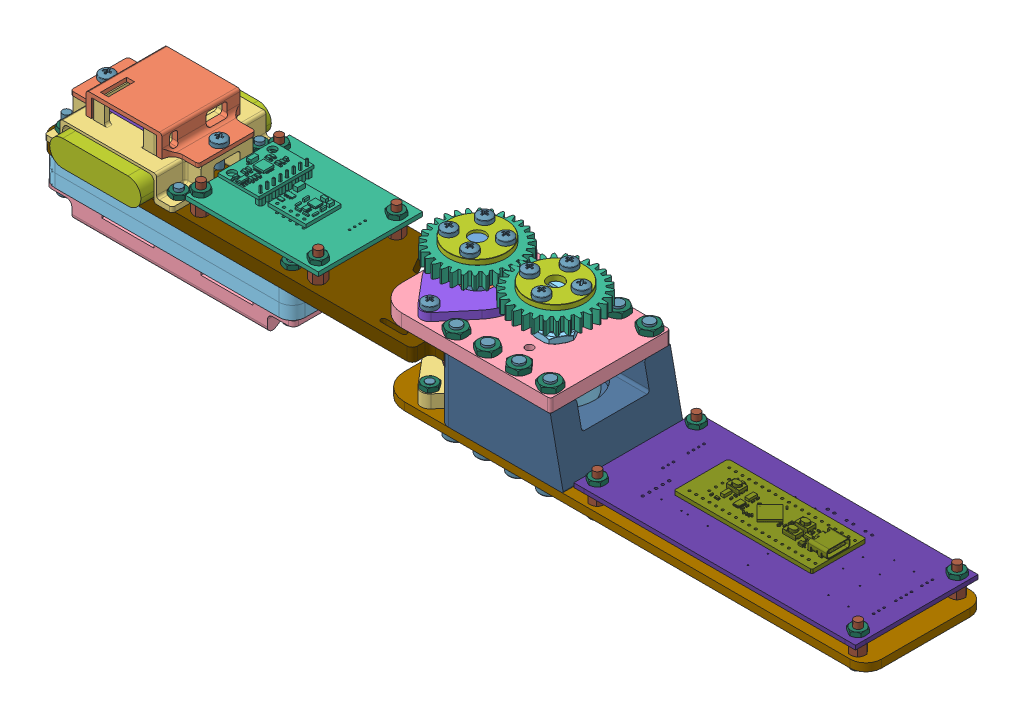
SolidWorks assembly canh_tay_cang_tay_asm, configuration Default. Lengths in mm.
Overall size (320 57.82 50).
135 component instances, 26 part files, 3 mates.
Components (placement in the parent):
- phan_cang_tay_asm-1: phan_cang_tay_asm [Default] at (73.3024 69.8746 76.7713) size (193.86 57.82 47.69)
  - truc_khuy_tay_6mm-1: truc_khuy_tay_6mm [Default] at (-13.0536 7.0359 41.2843) size (6 45 6)
  - instrument ball bearing_68_am-1: instrument ball bearing_68_am [AFBMA 12.1.4.1 - 0060-19 - 8,DE,NC,8_68] at (-13.0536 10.0359 41.2843) x (0 -1 0) z (0.814441 0 0.580247) size (6 19 19)
  - instrument ball bearing_68_am-2: instrument ball bearing_68_am [AFBMA 12.1.4.1 - 0060-19 - 8,DE,NC,8_68] at (-13.0536 33.0359 41.2843) x (0 -1 0) z (0.463151 0 0.88628) size (6 19 19)
  - thanh_noi_cang_tay_1-1: thanh_noi_cang_tay_1 [Default] at (-13.0536 7.0359 41.2843) x (-1 0 0) z (0 0 -1) size (30 5 43)
  - khuy_tay-1: khuy_tay [Default] at (16.9464 36.0359 41.2843) x (-1 0 0) z (0 -1 0) size (67 46 5)
  - RV24 v6.step-1: RV24 v6.step [Default] at (16.9464 24.0359 41.2843) x (0 1 0) z (0 0 -1) size (34 30.6 24.6)
  - banh_rang-1: banh_rang [Default] at (-13.8942 39.1454 73.2027) x (0 1 0) z (-0.508693 0 -0.860948) size (12 31.88 32)
    - spur gear_iso_m3-1: spur gear_iso_m3 [ISO - Spur gear 1M 30T 20PA 10FW ---S30B25H18L6.0N] at (1.8905 16.9604 27.0525) size (5 31.88 32)
    - mat_bich_6mm-1: mat_bich_6mm [Default] at (13.8905 16.9604 27.0525) x (0 0 1) z (0 -1 0) size (22 12 22)
  - mieng_che_o_lan-1: mieng_che_o_lan [Default] at (-13.0536 36.0359 41.2843) x (-1 0 0) z (0 0 -1) size (30 3 43)
  - thanh_cang_tay-1: thanh_cang_tay [Default] at (102.9464 4.0359 41.2843) x (-1 0 0) z (0 1 0) size (187 46 3)
  - noi_cang_tay-1: noi_cang_tay [Default] at (21.9464 7.0359 41.2843) x (-1 0 0) z (0 0 -1) size (47.89 24 46)
  - hexagonal_spacer_MF_M3_H05_HEX5_FTD3_MTL8.step-2: hexagonal_spacer_MF_M3_H05_HEX5_FTD3_MTL8.step [Default] at (151.9464 12.0359 60.2843) x (-0.310043 0 0.950723) z (0 -1 0) size (5.78 5.01 10.97)
  - mieng_dem_cang_tay-1: mieng_dem_cang_tay [Default] at (117.9464 4.0359 41.2843) x (-1 0 0) z (0 0 -1) size (70 6.47 35)
  - mieng_dem_cang_tay_2-1: mieng_dem_cang_tay_2 [Default] at (30.9464 4.0359 41.2843) x (-1 0 0) z (0 0 -1) size (68 6.47 30)
  - pan head cross recess screw_iso-1: pan head cross recess screw_iso [ISO 7045 - M3 x 8 - Z - 8N] at (147.9464 -0.3641 27.2843) x (0 1 0) z (0 0 1) size (10.35 5.6 5.6)
  - pan head cross recess screw_iso-2: pan head cross recess screw_iso [ISO 7045 - M3 x 8 - Z - 8N] at (147.9464 -0.3641 55.2843) x (0 1 0) z (0 0 1) size (10.35 5.6 5.6)
  - pan head cross recess screw_iso-3: pan head cross recess screw_iso [ISO 7045 - M3 x 8 - Z - 8N] at (87.9464 -0.3641 55.2843) x (0 1 0) z (0 0 1) size (10.35 5.6 5.6)
  - pan head cross recess screw_iso-4: pan head cross recess screw_iso [ISO 7045 - M3 x 8 - Z - 8N] at (87.9464 -0.3641 27.2843) x (0 1 0) z (0 0 1) size (10.35 5.6 5.6)
  - pan head cross recess screw_iso-5: pan head cross recess screw_iso [ISO 7045 - M3 x 8 - Z - 8N] at (60.9464 -0.3641 52.2843) x (0 1 0) z (0 0 1) size (10.35 5.6 5.6)
  - pan head cross recess screw_iso-6: pan head cross recess screw_iso [ISO 7045 - M3 x 8 - Z - 8N] at (60.9464 -0.3641 30.2843) x (0 1 0) z (0 0 1) size (10.35 5.6 5.6)
  - pan head cross recess screw_iso-9: pan head cross recess screw_iso [ISO 7045 - M3 x 6 - Z - 6N] at (0.9464 9.4359 30.2843) x (0 -1 0) z (0 0 1) size (8.35 5.6 5.6)
  - pan head cross recess screw_iso-10: pan head cross recess screw_iso [ISO 7045 - M3 x 6 - Z - 6N] at (0.9464 9.4359 52.2843) x (0 -1 0) z (0 0 1) size (8.35 5.6 5.6)
  - hex thin nut chamfered gradeab_iso-3: hex thin nut chamfered gradeab_iso [ISO - 4035 - M3 - N] at (0.9464 0.2359 30.2843) x (1 0 0) z (0 -1 0) size (5.5 6.35 1.8)
  - hex thin nut chamfered gradeab_iso-4: hex thin nut chamfered gradeab_iso [ISO - 4035 - M3 - N] at (0.9464 0.2359 52.2843) x (1 0 0) z (0 -1 0) size (5.5 6.35 1.8)
  - hex thin nut chamfered gradeab_iso-5: hex thin nut chamfered gradeab_iso [ISO - 4035 - M3 - N] at (60.9464 8.8359 30.2843) x (1 0 0) z (0 1 0) size (5.5 6.35 1.8)
  - hex thin nut chamfered gradeab_iso-6: hex thin nut chamfered gradeab_iso [ISO - 4035 - M3 - N] at (60.9464 8.8359 52.2843) x (1 0 0) z (0 1 0) size (5.5 6.35 1.8)
  - hex thin nut chamfered gradeab_iso-7: hex thin nut chamfered gradeab_iso [ISO - 4035 - M3 - N] at (87.9464 8.8359 55.2843) x (1 0 0) z (0 1 0) size (5.5 6.35 1.8)
  - hex thin nut chamfered gradeab_iso-8: hex thin nut chamfered gradeab_iso [ISO - 4035 - M3 - N] at (87.9464 8.8359 27.2843) x (1 0 0) z (0 1 0) size (5.5 6.35 1.8)
  - hex thin nut chamfered gradeab_iso-9: hex thin nut chamfered gradeab_iso [ISO - 4035 - M3 - N] at (147.9464 8.8359 27.2843) x (1 0 0) z (0 1 0) size (5.5 6.35 1.8)
  - hex thin nut chamfered gradeab_iso-10: hex thin nut chamfered gradeab_iso [ISO - 4035 - M3 - N] at (147.9464 8.8359 55.2843) x (1 0 0) z (0 1 0) size (5.5 6.35 1.8)
  - pan head cross recess screw_iso-18: pan head cross recess screw_iso [ISO 7045 - M4 x 35 - Z - 35N] at (33.9464 0.9359 22.2843) x (0 1 0) z (0 0 1) size (38.02 8 8)
  - pan head cross recess screw_iso-19: pan head cross recess screw_iso [ISO 7045 - M4 x 35 - Z - 35N] at (21.9464 0.9359 22.2843) x (0 1 0) z (0 0 1) size (38.02 8 8)
  - pan head cross recess screw_iso-20: pan head cross recess screw_iso [ISO 7045 - M4 x 35 - Z - 35N] at (9.9464 0.9359 22.2843) x (0 1 0) z (0 0 1) size (38.02 8 8)
  - pan head cross recess screw_iso-21: pan head cross recess screw_iso [ISO 7045 - M4 x 35 - Z - 35N] at (33.9464 0.9359 60.2843) x (0 1 0) z (0 0 1) size (38.02 8 8)
  - pan head cross recess screw_iso-22: pan head cross recess screw_iso [ISO 7045 - M4 x 35 - Z - 35N] at (21.9464 0.9359 60.2843) x (0 1 0) z (0 0 1) size (38.02 8 8)
  - pan head cross recess screw_iso-23: pan head cross recess screw_iso [ISO 7045 - M4 x 35 - Z - 35N] at (9.9464 0.9359 60.2843) x (0 1 0) z (0.916024 0 0.401125) size (38.02 8 8)
  - hex thin nut chamfered gradeab_iso-11: hex thin nut chamfered gradeab_iso [ISO - 4035 - M4 - N] at (33.9464 38.2359 22.2843) x (1 0 0) z (0 1 0) size (7 8.08 2.2)
  - hex thin nut chamfered gradeab_iso-12: hex thin nut chamfered gradeab_iso [ISO - 4035 - M4 - N] at (21.9464 38.2359 22.2843) x (1 0 0) z (0 1 0) size (7 8.08 2.2)
  - hex thin nut chamfered gradeab_iso-13: hex thin nut chamfered gradeab_iso [ISO - 4035 - M4 - N] at (9.9464 38.2359 22.2843) x (1 0 0) z (0 1 0) size (7 8.08 2.2)
  - hex thin nut chamfered gradeab_iso-14: hex thin nut chamfered gradeab_iso [ISO - 4035 - M4 - N] at (33.9464 36.0359 60.2843) x (0.993976 0 -0.109599) z (0 -1 0) size (7 8.08 2.2)
  - hex thin nut chamfered gradeab_iso-15: hex thin nut chamfered gradeab_iso [ISO - 4035 - M4 - N] at (21.9464 38.2359 60.2843) x (-0.185733 0 -0.9826) z (0 1 0) size (7 8.08 2.2)
  - hex thin nut chamfered gradeab_iso-16: hex thin nut chamfered gradeab_iso [ISO - 4035 - M4 - N] at (9.9464 38.2359 60.2843) x (1 0 0) z (0 1 0) size (7 8.08 2.2)
  - pan head cross recess screw_iso-25: pan head cross recess screw_iso [ISO 7045 - M3 x 10 - Z - 10N] at (-6.166 55.4359 37.2148) x (0 -1 0) z (0 0 1) size (12.35 5.6 5.6)
  - pan head cross recess screw_iso-26: pan head cross recess screw_iso [ISO 7045 - M3 x 10 - Z - 10N] at (-8.9841 55.4359 48.1719) x (0 -1 0) z (0 0 1) size (12.35 5.6 5.6)
  - pan head cross recess screw_iso-27: pan head cross recess screw_iso [ISO 7045 - M3 x 10 - Z - 10N] at (-19.9412 55.4359 45.3539) x (0 -1 0) z (-0.140483 0 -0.990083) size (12.35 5.6 5.6)
  - pan head cross recess screw_iso-28: pan head cross recess screw_iso [ISO 7045 - M3 x 10 - Z - 10N] at (-17.1232 55.4359 34.3967) x (0 -1 0) z (0 0 1) size (12.35 5.6 5.6)
  - pan head cross recess screw_iso-29: pan head cross recess screw_iso [ISO 7045 - M3 x 10 - Z - 10N] at (24.6096 55.4359 38.9877) x (0 -1 0) z (-0.805474 0 0.592631) size (12.35 5.6 5.6)
  - pan head cross recess screw_iso-30: pan head cross recess screw_iso [ISO 7045 - M3 x 10 - Z - 10N] at (14.6497 55.4359 33.6211) x (0 -1 0) z (0 0 1) size (12.35 5.6 5.6)
  - pan head cross recess screw_iso-31: pan head cross recess screw_iso [ISO 7045 - M3 x 10 - Z - 10N] at (9.2831 55.4359 43.581) x (0 -1 0) z (0 0 1) size (12.35 5.6 5.6)
  - pan head cross recess screw_iso-32: pan head cross recess screw_iso [ISO 7045 - M3 x 10 - Z - 10N] at (19.243 55.4359 48.9476) x (0 -1 0) z (0 0 1) size (12.35 5.6 5.6)
  - banh_rang-3: banh_rang [Default] at (47.7291 39.1454 49.7644) x (0 1 0) z (-0.957906 0 0.287083) size (12 31.88 32)
    - spur gear_iso_m3-1: spur gear_iso_m3 [ISO - Spur gear 1M 30T 20PA 10FW ---S30B25H18L6.0N] at (1.8905 16.9604 27.0525) size (5 31.88 32)
    - mat_bich_6mm-1: mat_bich_6mm [Default] at (13.8905 16.9604 27.0525) x (0 0 1) z (0 -1 0) size (22 12 22)
  - hex thin nut chamfered gradeab_iso-18: hex thin nut chamfered gradeab_iso [ISO - 4035 - M3 - N] at (19.243 44.2359 48.9476) x (1 0 0) z (0 -1 0) size (5.5 6.35 1.8)
  - hex thin nut chamfered gradeab_iso-19: hex thin nut chamfered gradeab_iso [ISO - 4035 - M3 - N] at (9.2831 44.2359 43.581) x (1 0 0) z (0 -1 0) size (5.5 6.35 1.8)
  - hex thin nut chamfered gradeab_iso-20: hex thin nut chamfered gradeab_iso [ISO - 4035 - M3 - N] at (14.6497 44.2359 33.6211) x (1 0 0) z (0 -1 0) size (5.5 6.35 1.8)
  - hex thin nut chamfered gradeab_iso-21: hex thin nut chamfered gradeab_iso [ISO - 4035 - M3 - N] at (24.6096 44.2359 38.9877) x (1 0 0) z (0 -1 0) size (5.5 6.35 1.8)
  - hex thin nut chamfered gradeab_iso-22: hex thin nut chamfered gradeab_iso [ISO - 4035 - M3 - N] at (-6.166 44.2359 37.2148) x (1 0 0) z (0 -1 0) size (5.5 6.35 1.8)
  - hex thin nut chamfered gradeab_iso-23: hex thin nut chamfered gradeab_iso [ISO - 4035 - M3 - N] at (-8.9841 44.2359 48.1719) x (1 0 0) z (0 -1 0) size (5.5 6.35 1.8)
  - hex thin nut chamfered gradeab_iso-24: hex thin nut chamfered gradeab_iso [ISO - 4035 - M3 - N] at (-17.1232 44.2359 34.3967) x (1 0 0) z (0 -1 0) size (5.5 6.35 1.8)
  - hex thin nut chamfered gradeab_iso-25: hex thin nut chamfered gradeab_iso [ISO - 4035 - M3 - N] at (-19.9412 44.2359 45.3539) x (1 0 0) z (0 -1 0) size (5.5 6.35 1.8)
  - pan head cross recess screw_iso-37: pan head cross recess screw_iso [ISO 7045 - M3 x 10 - Z - 10N] at (-13.0536 41.4359 59.5343) x (0 -1 0) z (0 0 1) size (12.35 5.6 5.6)
  - pan head cross recess screw_iso-38: pan head cross recess screw_iso [ISO 7045 - M3 x 10 - Z - 10N] at (-13.0536 41.4359 23.0343) x (0 -1 0) z (0 0 1) size (12.35 5.6 5.6)
  - pan head cross recess screw_iso-39: pan head cross recess screw_iso [ISO 7045 - M3 x 10 - Z - 10N] at (-13.0536 1.6359 59.5343) x (0 1 0) z (0 0 1) size (12.35 5.6 5.6)
  - pan head cross recess screw_iso-40: pan head cross recess screw_iso [ISO 7045 - M3 x 10 - Z - 10N] at (-13.0536 1.6359 23.0343) x (0 1 0) z (0 0 1) size (12.35 5.6 5.6)
  - hex thin nut chamfered gradeab_iso-30: hex thin nut chamfered gradeab_iso [ISO - 4035 - M3 - N] at (-13.0536 29.2359 23.0343) x (1 0 0) z (0 -1 0) size (5.5 6.35 1.8)
  - hex thin nut chamfered gradeab_iso-31: hex thin nut chamfered gradeab_iso [ISO - 4035 - M3 - N] at (-13.0536 13.8359 23.0343) x (1 0 0) z (0 1 0) size (5.5 6.35 1.8)
  - hex thin nut chamfered gradeab_iso-33: hex thin nut chamfered gradeab_iso [ISO - 4035 - M3 - N] at (-13.0536 12.0359 59.5343) x (0.832178 0 -0.554509) z (0 -1 0) size (5.5 6.35 1.8)
  - hex thin nut chamfered gradeab_iso-34: hex thin nut chamfered gradeab_iso [ISO - 4035 - M3 - N] at (-13.0536 29.2359 59.5343) x (1 0 0) z (0 -1 0) size (5.5 6.35 1.8)
  - pan head cross recess screw_iso-59: pan head cross recess screw_iso [ISO 7045 - M4 x 35 - Z - 35N] at (-2.0536 0.9359 60.2843) x (0 1 0) z (-0.660079 0 0.751196) size (38.02 8 8)
  - hex thin nut chamfered gradeab_iso-45: hex thin nut chamfered gradeab_iso [ISO - 4035 - M4 - N] at (-2.0536 38.2359 60.2843) x (1 0 0) z (0 1 0) size (7 8.08 2.2)
  - hexagonal_spacer_MF_M3_H05_HEX5_FTD3_MTL8.step-3: hexagonal_spacer_MF_M3_H05_HEX5_FTD3_MTL8.step [Default] at (151.9464 12.0359 22.2843) x (-0.310043 0 0.950723) z (0 -1 0) size (5.78 5.01 10.97)
  - hexagonal_spacer_MF_M3_H05_HEX5_FTD3_MTL8.step-4: hexagonal_spacer_MF_M3_H05_HEX5_FTD3_MTL8.step [Default] at (51.9464 12.0359 60.2843) x (-0.310043 0 0.950723) z (0 -1 0) size (5.78 5.01 10.97)
  - hexagonal_spacer_MF_M3_H05_HEX5_FTD3_MTL8.step-5: hexagonal_spacer_MF_M3_H05_HEX5_FTD3_MTL8.step [Default] at (51.9464 12.0359 22.2843) x (-0.310043 0 0.950723) z (0 -1 0) size (5.78 5.01 10.97)
  - pan head cross recess screw_iso-60: pan head cross recess screw_iso [ISO 7045 - M3 x 8 - Z - 8N] at (151.9464 1.6359 22.2843) x (0 1 0) z (0 0 1) size (10.35 5.6 5.6)
  - pan head cross recess screw_iso-61: pan head cross recess screw_iso [ISO 7045 - M3 x 8 - Z - 8N] at (151.9464 1.6359 60.2843) x (0 1 0) z (0 0 1) size (10.35 5.6 5.6)
  - pan head cross recess screw_iso-62: pan head cross recess screw_iso [ISO 7045 - M3 x 8 - Z - 8N] at (51.9464 1.6359 60.2843) x (0 1 0) z (0 0 1) size (10.35 5.6 5.6)
  - pan head cross recess screw_iso-63: pan head cross recess screw_iso [ISO 7045 - M3 x 8 - Z - 8N] at (51.9464 1.6359 22.2843) x (0 1 0) z (0 0 1) size (10.35 5.6 5.6)
  - control_glove_v0.1.step-1: control_glove_v0.1.step [Default] at (56.9464 12.0359 56.2843) x (1 0 0) z (0 1 0) size (108 47 7.4)
    - MiniF4x1Cx_V31_3D.step-1: MiniF4x1Cx_V31_3D.step [Default] at (68.0647 25.992 4.15) x (-1 0 0) z (0 0 1) size (52.81 20.78 5.3)
      - COMPOUND.step-1: COMPOUND.step [Default] at origin size (52.81 20.78 5.3)
    - _autosave-control_glove_v0.1 PCB.step-1: _autosave-control_glove_v0.1 PCB.step [Default] at origin size (108 47 1.6)
  - hex thin nut chamfered gradeab_iso-46: hex thin nut chamfered gradeab_iso [ISO - 4035 - M3 - N] at (51.9464 15.4359 22.2843) x (1 0 0) z (0 1 0) size (5.5 6.35 1.8)
  - hex thin nut chamfered gradeab_iso-47: hex thin nut chamfered gradeab_iso [ISO - 4035 - M3 - N] at (51.9464 15.4359 60.2843) x (1 0 0) z (0 1 0) size (5.5 6.35 1.8)
  - hex thin nut chamfered gradeab_iso-48: hex thin nut chamfered gradeab_iso [ISO - 4035 - M3 - N] at (151.9464 15.4359 22.2843) x (1 0 0) z (0 1 0) size (5.5 6.35 1.8)
  - hex thin nut chamfered gradeab_iso-49: hex thin nut chamfered gradeab_iso [ISO - 4035 - M3 - N] at (151.9464 15.4359 60.2843) x (1 0 0) z (0 1 0) size (5.5 6.35 1.8)
- phan_canh_tay_asm-1: phan_canh_tay_asm [Default] at (-0.0131 19.8199 138.0557) size (161 41.97 50)
  - thanh_khuy_tay-1: thanh_khuy_tay [Default] at (60.2619 70.5906 -20) x (-1 0 0) z (0 1 0) size (161 40 5)
  - mat_bich_6mm-1: mat_bich_6mm [Default] at (60.2619 75.0906 -20) x (-1 0 0) z (0 0 1) size (22 12 22)
  - dem_mat_bich-2: dem_mat_bich [Default] at (60.2619 75.0906 -20) x (0 0 1) z (-1 0 0) size (22 5 22)
  - hexagonal_spacer_MF_M3_H05_HEX5_FTD3_MTL8.step-1: hexagonal_spacer_MF_M3_H05_HEX5_FTD3_MTL8.step [Default] at (14.2619 78.0906 -35) x (-0.957206 0 -0.289407) z (0 -1 0) size (5.78 5.01 10.97)
  - nap_mach_sac-1: nap_mach_sac [Default] at (-60.2381 83.0906 -20) x (-1 0 0) z (0 0 -1) size (49 8.5 30)
  - vo_pin-1: vo_pin [Default] at (-60.2381 83.0906 -20) x (-1 0 0) z (0 0 -1) size (49 17 42)
  - mieng_dem_canh_tay - 2-1: mieng_dem_canh_tay - 2 [Default] at (-30.7381 58.0906 -20) x (-1 0 0) z (0 0 -1) size (95 8.47 38)
  - mieng_lot_dem_canh_tay_1-3: mieng_lot_dem_canh_tay_1 [Default] at (-30.7381 63.0906 -20) x (-1 0 0) z (0 0 -1) size (96 5 40)
  - mieng_lot_dem_canh_tay_1-4: mieng_lot_dem_canh_tay_1 [Default] at (-30.7381 58.0906 -20) x (-1 0 0) z (0 0 -1) size (96 5 40)
  - pan head cross recess screw_iso-33: pan head cross recess screw_iso [ISO 7045 - M3 x 10 - Z - 10N] at (68.2619 78.4906 -20) x (0 -1 0) z (0.29969 0 0.954037) size (12.35 5.6 5.6)
  - pan head cross recess screw_iso-34: pan head cross recess screw_iso [ISO 7045 - M3 x 10 - Z - 10N] at (60.2619 78.4906 -12) x (0 -1 0) z (0.29969 0 0.954037) size (12.35 5.6 5.6)
  - pan head cross recess screw_iso-35: pan head cross recess screw_iso [ISO 7045 - M3 x 10 - Z - 10N] at (52.2619 78.4906 -20) x (0 -1 0) z (0.29969 0 0.954037) size (12.35 5.6 5.6)
  - pan head cross recess screw_iso-36: pan head cross recess screw_iso [ISO 7045 - M3 x 10 - Z - 10N] at (60.2619 78.4906 -28) x (0 -1 0) z (0.29969 0 0.954037) size (12.35 5.6 5.6)
  - hex thin nut chamfered gradeab_iso-26: hex thin nut chamfered gradeab_iso [ISO - 4035 - M3 - N] at (52.2619 66.2906 -20) x (0.954037 0 -0.29969) z (0 -1 0) size (5.5 6.35 1.8)
  - hex thin nut chamfered gradeab_iso-27: hex thin nut chamfered gradeab_iso [ISO - 4035 - M3 - N] at (60.2619 66.2906 -28) x (0.954037 0 -0.29969) z (0 -1 0) size (5.5 6.35 1.8)
  - hex thin nut chamfered gradeab_iso-28: hex thin nut chamfered gradeab_iso [ISO - 4035 - M3 - N] at (60.2619 66.2906 -12) x (0.954037 0 -0.29969) z (0 -1 0) size (5.5 6.35 1.8)
  - hex thin nut chamfered gradeab_iso-29: hex thin nut chamfered gradeab_iso [ISO - 4035 - M3 - N] at (68.2619 66.2906 -20) x (0.954037 0 -0.29969) z (0 -1 0) size (5.5 6.35 1.8)
  - pan head cross recess screw_iso-41: pan head cross recess screw_iso [ISO 7045 - M3 x 20 - Z - 20N] at (4.2619 53.6906 -35) x (0 1 0) z (0.29969 0 0.954037) size (22.35 5.6 5.6)
  - pan head cross recess screw_iso-42: pan head cross recess screw_iso [ISO 7045 - M3 x 20 - Z - 20N] at (4.2619 53.6906 -5) x (0 1 0) z (0.29969 0 0.954037) size (22.35 5.6 5.6)
  - pan head cross recess screw_iso-43: pan head cross recess screw_iso [ISO 7045 - M3 x 20 - Z - 20N] at (-30.7381 53.6906 -5) x (0 1 0) z (0.29969 0 0.954037) size (22.35 5.6 5.6)
  - pan head cross recess screw_iso-44: pan head cross recess screw_iso [ISO 7045 - M3 x 20 - Z - 20N] at (-30.7381 53.6906 -35) x (0 1 0) z (0.29969 0 0.954037) size (22.35 5.6 5.6)
  - pan head cross recess screw_iso-47: pan head cross recess screw_iso [ISO 7045 - M3 x 8 - Z - 8N] at (14.2619 65.6906 -5) x (0 1 0) z (0.29969 0 0.954037) size (10.35 5.6 5.6)
  - pan head cross recess screw_iso-48: pan head cross recess screw_iso [ISO 7045 - M3 x 8 - Z - 8N] at (14.2619 65.6906 -35) x (0 1 0) z (0.29969 0 0.954037) size (10.35 5.6 5.6)
  - pan head cross recess screw_iso-51: pan head cross recess screw_iso [ISO 7045 - M3 x 8 - Z - 8N] at (-38.7381 67.6906 -4.5) x (0 1 0) z (0.29969 0 0.954037) size (10.35 5.6 5.6)
  - pan head cross recess screw_iso-52: pan head cross recess screw_iso [ISO 7045 - M3 x 8 - Z - 8N] at (-38.7381 67.6906 -35.5) x (0 1 0) z (0.29969 0 0.954037) size (10.35 5.6 5.6)
  - pan head cross recess screw_iso-53: pan head cross recess screw_iso [ISO 7045 - M3 x 8 - Z - 8N] at (-81.7381 86.9906 -20) x (0 -1 0) z (0.29969 0 0.954037) size (10.35 5.6 5.6)
  - pan head cross recess screw_iso-54: pan head cross recess screw_iso [ISO 7045 - M3 x 8 - Z - 8N] at (-38.7381 86.9906 -20) x (0 -1 0) z (0.29969 0 0.954037) size (10.35 5.6 5.6)
  - pan head cross recess screw_iso-55: pan head cross recess screw_iso [ISO 7045 - M3 x 25 - Z - 25N] at (-81.7381 53.6906 -35.5) x (0 1 0) z (0.29969 0 0.954037) size (27.35 5.6 5.6)
  - pan head cross recess screw_iso-56: pan head cross recess screw_iso [ISO 7045 - M3 x 25 - Z - 25N] at (-81.7381 53.6906 -4.5) x (0 1 0) z (0.29969 0 0.954037) size (27.35 5.6 5.6)
  - hex thin nut chamfered gradeab_iso-35: hex thin nut chamfered gradeab_iso [ISO - 4035 - M3 - N] at (-81.7381 76.8906 -4.5) x (0.954037 0 -0.29969) z (0 1 0) size (5.5 6.35 1.8)
  - hex thin nut chamfered gradeab_iso-36: hex thin nut chamfered gradeab_iso [ISO - 4035 - M3 - N] at (-81.7381 76.8906 -35.5) x (0.954037 0 -0.29969) z (0 1 0) size (5.5 6.35 1.8)
  - hex thin nut chamfered gradeab_iso-37: hex thin nut chamfered gradeab_iso [ISO - 4035 - M3 - N] at (-38.7381 76.8906 -35.5) x (0.954037 0 -0.29969) z (0 1 0) size (5.5 6.35 1.8)
  - hex thin nut chamfered gradeab_iso-39: hex thin nut chamfered gradeab_iso [ISO - 4035 - M3 - N] at (4.2619 74.8906 -35) x (0.954037 0 -0.29969) z (0 1 0) size (5.5 6.35 1.8)
  - hex thin nut chamfered gradeab_iso-40: hex thin nut chamfered gradeab_iso [ISO - 4035 - M3 - N] at (4.2619 74.8906 -5) x (0.954037 0 -0.29969) z (0 1 0) size (5.5 6.35 1.8)
  - hex thin nut chamfered gradeab_iso-41: hex thin nut chamfered gradeab_iso [ISO - 4035 - M3 - N] at (-38.7381 76.8906 -4.5) x (0.954037 0 -0.29969) z (0 1 0) size (5.5 6.35 1.8)
  - hex thin nut chamfered gradeab_iso-42: hex thin nut chamfered gradeab_iso [ISO - 4035 - M3 - N] at (-81.7381 79.2906 -20) x (0.954037 0 -0.29969) z (0 -1 0) size (5.5 6.35 1.8)
  - hexagonal_spacer_MF_M3_H05_HEX5_FTD3_MTL8.step-3: hexagonal_spacer_MF_M3_H05_HEX5_FTD3_MTL8.step [Default] at (14.2619 78.0906 -5) x (-0.957206 0 -0.289407) z (0 -1 0) size (5.78 5.01 10.97)
  - hexagonal_spacer_MF_M3_H05_HEX5_FTD3_MTL8.step-4: hexagonal_spacer_MF_M3_H05_HEX5_FTD3_MTL8.step [Default] at (-30.7381 78.0906 -5) x (-0.957206 0 -0.289407) z (0 -1 0) size (5.78 5.01 10.97)
  - hexagonal_spacer_MF_M3_H05_HEX5_FTD3_MTL8.step-5: hexagonal_spacer_MF_M3_H05_HEX5_FTD3_MTL8.step [Default] at (-30.7381 78.0906 -35) x (-0.957206 0 -0.289407) z (0 -1 0) size (5.78 5.01 10.97)
  - shoulder_module_v0.1.step-2: shoulder_module_v0.1.step [Default] at (-19.7381 78.0906 -143) x (0 0 1) z (0 1 0) size (40 51 11.18)
  - pin_lipoSLDPRT-1: pin_lipoSLDPRT [Default] at (-60.2381 72.0906 -19) size (35 10 50)
  - mach_sac-1: mach_sac [Default] at (-60.2381 86.0906 -20.5) x (-1 0 0) z (0 0 -1) size (20 4 28)
  - hex thin nut chamfered gradeab_iso-44: hex thin nut chamfered gradeab_iso [ISO - 4035 - M3 - N] at (14.2619 81.4906 -35) x (1 0 0) z (0 1 0) size (5.5 6.35 1.8)
  - hex thin nut chamfered gradeab_iso-45: hex thin nut chamfered gradeab_iso [ISO - 4035 - M3 - N] at (14.2619 81.4906 -5) x (1 0 0) z (0 1 0) size (5.5 6.35 1.8)
  - hex thin nut chamfered gradeab_iso-46: hex thin nut chamfered gradeab_iso [ISO - 4035 - M3 - N] at (-30.7381 81.4906 -35) x (1 0 0) z (0 1 0) size (5.5 6.35 1.8)
  - hex thin nut chamfered gradeab_iso-47: hex thin nut chamfered gradeab_iso [ISO - 4035 - M3 - N] at (-30.7381 81.4906 -5) x (1 0 0) z (0 1 0) size (5.5 6.35 1.8)
Mates (geometry in assembly coordinates):
- Concentric1: concentric aligned: cylinder of phan_cang_tay_asm-1/truc_khuy_tay_6mm-1 through (60.2488 121.9105 118.0557) axis (0 -1 0) radius 3; cylinder of phan_canh_tay_asm-1/dem_mat_bich-2 through (60.2488 99.9105 118.0557) axis (0 -1 0) radius 3
- Coincident1: coincident anti-aligned: plane of phan_cang_tay_asm-1/instrument ball bearing_68_am-2 through (63.1735 99.9105 116.5273) normal (0 -1 0); plane of phan_canh_tay_asm-1/dem_mat_bich-2 through (60.2488 99.9105 118.0557) normal (0 1 0)
- Parallel1: parallel aligned: plane of phan_cang_tay_asm-1/thanh_cang_tay-1 through (176.2488 76.9105 141.0557) normal (0 0 1); plane of phan_canh_tay_asm-1/thanh_khuy_tay-1 through (60.2488 92.9105 138.0557) normal (0 0 1)
